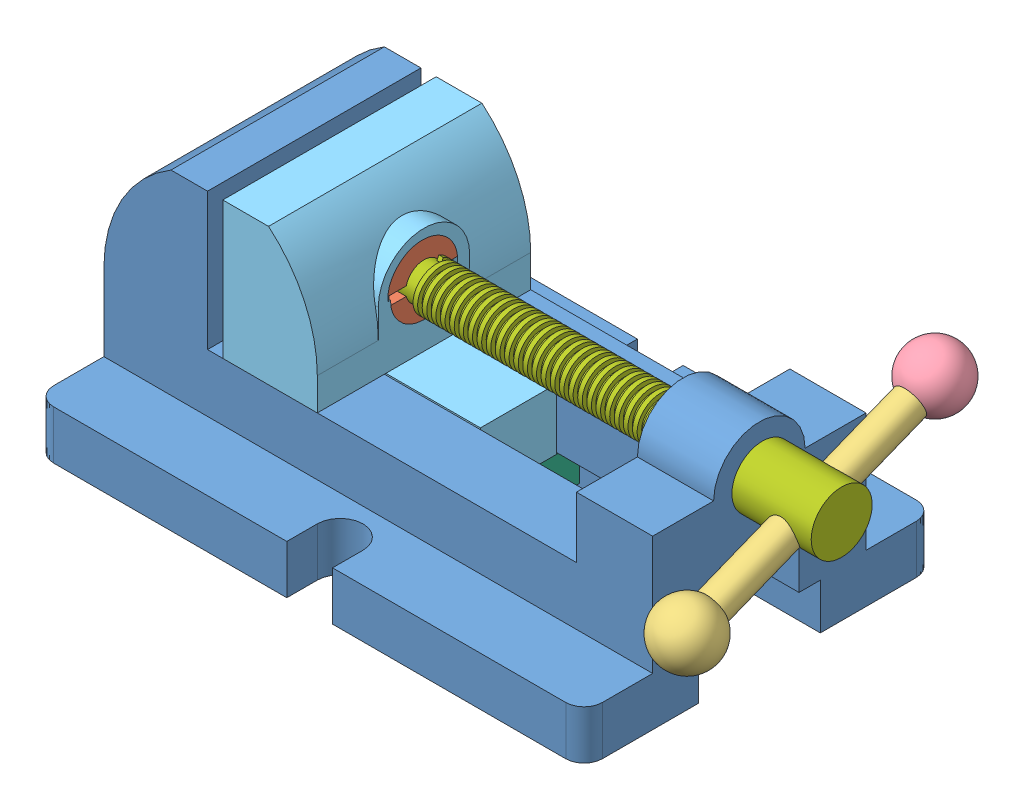
SolidWorks assembly Vice, configuration Default. Lengths in mm.
Overall size (210.77 87.67 115).
10 component instances, 9 part files, 19 mates.
Components (placement in the parent):
- Base-2: Base [Default] at (43.4856 80.4383 144.556) size (180 80 115)
- Bushing-2: Bushing [Default] at (13.4856 117.9383 144.556) x (-1 0 0) z (0 0 -1) size (20.59 25.41 24.6)
- Handle-2: Handle [Default] at (150.4856 116.5282 148.0934) x (0.850307 0.488879 0.194871) z (0.526286 -0.789869 -0.314848) size (20 100.37 20)
- Knob-2: Knob [Default] at (150.4856 134.1163 103.9697) x (0.850307 0.488879 0.194871) z (0.526286 -0.789869 -0.314848) size (20 18.66 20)
- MovableJaw-2: MovableJaw [Default] at (29.4856 97.9383 144.556) x (-1 0 0) z (0 0 -1) size (62 65 70)
- MovJawPlate-2: MovJawPlate [Default] at (23.4856 65.9383 144.556) x (0 0 -1) z (1 0 0) size (40 12 62)
- Screw-2: Screw [Default] at (77.9856 117.9383 144.556) x (-1 0 0) z (0 0.370275 -0.928922) size (165 20 20)
- Washer-2: Washer [Default] at (0.4856 117.9383 144.556) x (1 0 0) z (0 0.759033 0.651052) size (2 16.79 18)
- flat countersunk head tapping screw_am-1: flat countersunk head tapping screw_am [FLATCKT 8x20x13.3-slot-AB-N] at (4.4856 67.7168 144.556) x (0 1 0) z (-0.04419 0 0.999023) size (20.03 13.07 12.96)
- flat countersunk head tapping screw_am-2: flat countersunk head tapping screw_am [FLATCKT 8x20x13.3-slot-AB-N] at (42.4856 67.7168 144.556) x (0 1 0) z (0.028476 0 0.999594) size (20.03 13.07 12.96)
Mates (geometry in assembly coordinates):
- Coincident3: coincident aligned: plane of Base-2 through (133.4856 97.9383 157.556) normal (0 1 0); plane of MovableJaw-2 through (29.4856 97.9383 132.056) normal (0 1 0)
- Distance1: distance = 5 mm: line of MovableJaw-2 through (-7.5144 142.9383 109.556) axis (0 0 1); line of Base-2 through (-12.5144 142.9383 179.556) axis (0 0 -1)
- Concentric3: concentric anti-aligned: cylinder of Base-2 through (108.4856 117.9383 144.556) axis (1 0 0) radius 7.5; cylinder of Screw-2 through (-4.5144 117.9383 144.556) axis (-1 0 0) radius 6
- Concentric4: concentric anti-aligned: cylinder of Bushing-2 through (3.4856 117.9383 144.556) axis (-1 0 0) radius 9; cylinder of MovableJaw-2 through (1.4856 117.9383 144.556) axis (1 0 0) radius 9
- Coincident5: coincident anti-aligned: plane of MovableJaw-2 through (-4.5144 117.9383 144.556) normal (1 0 0); plane of Screw-2 through (-4.5144 123.5118 146.7776) normal (-1 0 0)
- Coincident6: coincident anti-aligned: plane of Bushing-2 through (13.4856 128.9383 144.556) normal (-1 0 0); plane of MovableJaw-2 through (13.4856 97.9383 144.556) normal (1 0 0)
- Concentric5: concentric anti-aligned: cylinder of Screw-2 through (-4.5144 117.9383 144.556) axis (-1 0 0) radius 4.5; circle of Washer-2
- Coincident7: coincident anti-aligned: plane of Screw-2 through (-0.5144 122.1184 146.2222) normal (1 0 0); plane of Washer-2 through (-0.5144 117.9383 144.556) normal (-1 0 0)
- Concentric6: concentric aligned: cylinder of Handle-2 through (150.4856 135.042 101.6473) axis (0 0.370275 -0.928922) radius 5; cylinder of Screw-2 through (150.4856 114.2355 153.8452) axis (0 0.370275 -0.928922) radius 5
- Coincident8: coincident anti-aligned: plane of Handle-2 through (150.4856 135.042 101.6473) normal (0 0.370275 -0.928922); plane of Knob-2 through (150.4856 135.042 101.6473) normal (0 -0.370275 0.928922)
- Concentric7: concentric anti-aligned: cylinder of Handle-2 through (150.4856 135.042 101.6473) axis (0 0.370275 -0.928922) radius 5; cylinder of Knob-2 through (150.4856 135.042 101.6473) axis (0 -0.370275 0.928922) radius 5
- Concentric8: concentric aligned: cylinder of MovableJaw-2 through (4.4856 77.9383 144.556) axis (0 -1 0) radius 4; cylinder of MovJawPlate-2 through (4.4856 65.9383 144.556) axis (0 -1 0) radius 4.5
- Concentric9: concentric aligned: cylinder of MovableJaw-2 through (42.4856 77.9383 144.556) axis (0 -1 0) radius 4; cylinder of MovJawPlate-2 through (42.4856 65.9383 144.556) axis (0 -1 0) radius 4.5
- Coincident9: coincident anti-aligned: plane of MovableJaw-2 through (54.4856 77.9383 132.056) normal (0 -1 0); plane of MovJawPlate-2 through (23.4856 77.9383 144.556) normal (0 1 0)
- Width1: width anti-aligned: plane of Base-2 through (133.4856 77.9383 131.556) normal (0 0 1); plane of MovableJaw-2 through (133.4856 77.9383 157.556) normal (0 0 -1); plane of Base-2 through (29.4856 97.9383 132.056) normal (0 0 -1); plane of MovableJaw-2 through (29.4856 97.9383 157.056) normal (0 0 1)
- Concentric10: concentric aligned: cone of MovJawPlate-2 through (4.4856 65.9383 144.556) axis (0 1 0); cone of flat countersunk head tapping screw_am-1 through (4.4856 71.8707 144.556) axis (0 1 0)
- Concentric11: concentric aligned: cone of MovJawPlate-2 through (42.4856 65.9383 144.556) axis (0 1 0); cone of flat countersunk head tapping screw_am-2 through (42.4856 71.8707 144.556) axis (0 1 0)
- Coincident10: coincident anti-aligned: cone of MovJawPlate-2 through (4.4856 65.9383 144.556) axis (0 1 0); circle of flat countersunk head tapping screw_am-1
- Coincident11: coincident anti-aligned: cone of MovJawPlate-2 through (42.4856 65.9383 144.556) axis (0 1 0); circle of flat countersunk head tapping screw_am-2
